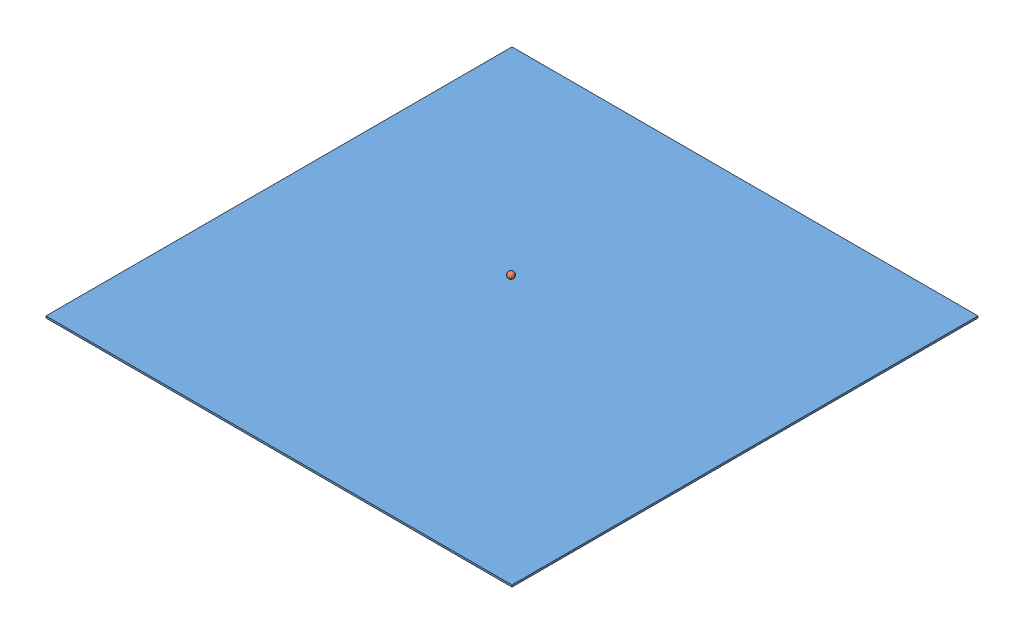
SolidWorks assembly ball simulation, configuration Default. Lengths in mm.
Overall size (5000 433.72 5000).
2 component instances, 2 part files, 0 mates.
Components (placement in the parent):
- ground-1: ground [Default] at origin size (5000 20 5000)
- ball-1: ball [Default] at (-6.7257 399.7207 4.2154) size (68 68 68)
